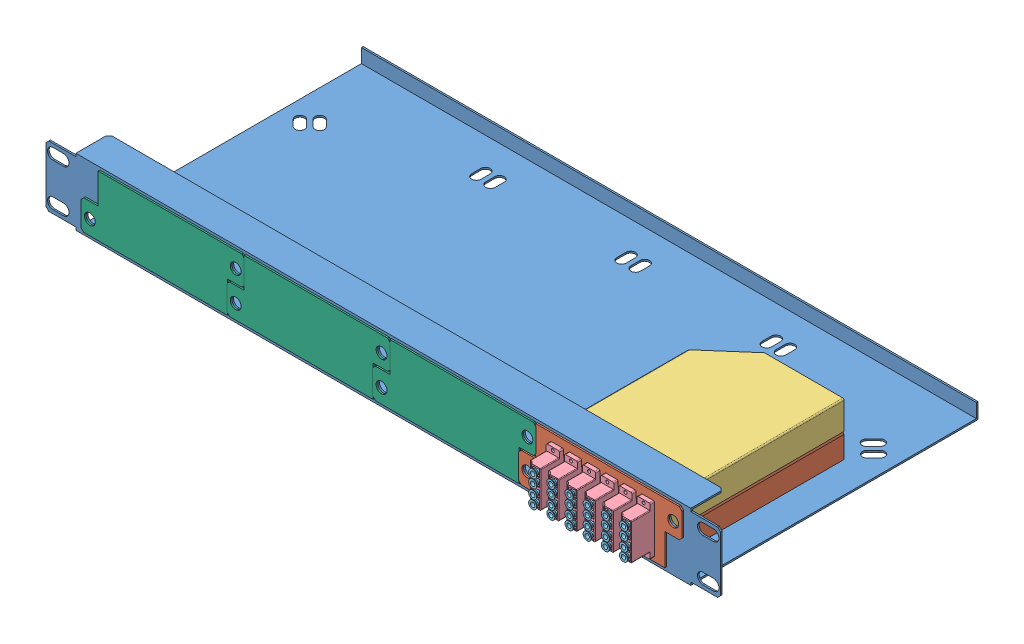
SolidWorks assembly MTP-Pannel, configuration Standard. Lengths in mm.
Overall size (482.6 47.8 225.51).
67 component instances, 6 part files, 15 mates.
Components (placement in the parent):
- 1U Rack Plate-1: 1U Rack Plate [Standard] at (-414.8398 -8.3387 0) size (482.6 47.8 205.5)
- MTP-Casette-1: MTP-Casette [Standard] at (-26.275 -1.825 1.2) size (117 43.2 150.01)
  - Cassette-1: Cassette [Standard] at (-81.5544 -7.2939 -1.2) size (117 43.2 131.2)
  - Cassette Lid-1: Cassette Lid [Standard] at (-38.8731 -6.65 -32.039) size (86.6 20.2 130)
  - LC-Adapter-1: LC-Adapter [Standard] at (-94.18 -5.525 16.25) x (0 1 0) z (0 0 1) size (34.9 10.05 34.47)
    - LC Adaptor-1: LC Adaptor [Standard] at (-28.4856 -9.35 -16.25) x (1 0 0) z (0 -1 0) size (34.9 25.75 9.35)
    - LC Adaptor Dust Cap-1: LC Adaptor Dust Cap [Standard] at (-27.05 -6.075 2.56) x (-0.837169 0.546944 0) z (-0.546944 -0.837169 0) size (5.75 16.66 5.75)
    - LC Adaptor Dust Cap-2: LC Adaptor Dust Cap [Standard] at (-20.85 -6.075 2.56) x (-0.837169 0.546944 0) z (-0.546944 -0.837169 0) size (5.75 16.66 5.75)
    - LC Adaptor Dust Cap-3: LC Adaptor Dust Cap [Standard] at (-14.05 -6.075 2.56) x (-0.837169 0.546944 0) z (-0.546944 -0.837169 0) size (5.75 16.66 5.75)
    - LC Adaptor Dust Cap-4: LC Adaptor Dust Cap [Standard] at (-7.85 -6.075 2.56) x (-0.837169 0.546944 0) z (-0.546944 -0.837169 0) size (5.75 16.66 5.75)
    - LC Adaptor Dust Cap-5: LC Adaptor Dust Cap [Standard] at (-27.05 -6.075 -31.91) x (0.972668 -0.232198 0) z (-0.232198 -0.972668 0) size (5.75 16.66 5.75)
    - LC Adaptor Dust Cap-6: LC Adaptor Dust Cap [Standard] at (-20.85 -6.075 -31.91) x (1 0 0) z (0 -1 0) size (5.75 16.66 5.75)
    - LC Adaptor Dust Cap-7: LC Adaptor Dust Cap [Standard] at (-14.05 -6.075 -31.91) x (0.97427 0.225385 0) z (0.225385 -0.97427 0) size (5.75 16.66 5.75)
    - LC Adaptor Dust Cap-8: LC Adaptor Dust Cap [Standard] at (-7.85 -6.075 -31.91) x (1 0 0) z (0 -1 0) size (5.75 16.66 5.75)
  - LC-Adapter-2: LC-Adapter [Standard] at (-81.18 -5.525 16.25) x (0 1 0) z (0 0 1) size (34.9 10.05 34.47)
    - LC Adaptor-1: LC Adaptor [Standard] at (-28.4856 -9.35 -16.25) x (1 0 0) z (0 -1 0) size (34.9 25.75 9.35)
    - LC Adaptor Dust Cap-1: LC Adaptor Dust Cap [Standard] at (-27.05 -6.075 2.56) x (-0.837169 0.546944 0) z (-0.546944 -0.837169 0) size (5.75 16.66 5.75)
    - LC Adaptor Dust Cap-2: LC Adaptor Dust Cap [Standard] at (-20.85 -6.075 2.56) x (-0.837169 0.546944 0) z (-0.546944 -0.837169 0) size (5.75 16.66 5.75)
    - LC Adaptor Dust Cap-3: LC Adaptor Dust Cap [Standard] at (-14.05 -6.075 2.56) x (-0.837169 0.546944 0) z (-0.546944 -0.837169 0) size (5.75 16.66 5.75)
    - LC Adaptor Dust Cap-4: LC Adaptor Dust Cap [Standard] at (-7.85 -6.075 2.56) x (-0.837169 0.546944 0) z (-0.546944 -0.837169 0) size (5.75 16.66 5.75)
    - LC Adaptor Dust Cap-5: LC Adaptor Dust Cap [Standard] at (-27.05 -6.075 -31.91) x (0.972668 -0.232198 0) z (-0.232198 -0.972668 0) size (5.75 16.66 5.75)
    - LC Adaptor Dust Cap-6: LC Adaptor Dust Cap [Standard] at (-20.85 -6.075 -31.91) x (1 0 0) z (0 -1 0) size (5.75 16.66 5.75)
    - LC Adaptor Dust Cap-7: LC Adaptor Dust Cap [Standard] at (-14.05 -6.075 -31.91) x (0.97427 0.225385 0) z (0.225385 -0.97427 0) size (5.75 16.66 5.75)
    - LC Adaptor Dust Cap-8: LC Adaptor Dust Cap [Standard] at (-7.85 -6.075 -31.91) x (1 0 0) z (0 -1 0) size (5.75 16.66 5.75)
  - LC-Adapter-3: LC-Adapter [Standard] at (-68.18 -5.525 16.25) x (0 1 0) z (0 0 1) size (34.9 10.05 34.47)
    - LC Adaptor-1: LC Adaptor [Standard] at (-28.4856 -9.35 -16.25) x (1 0 0) z (0 -1 0) size (34.9 25.75 9.35)
    - LC Adaptor Dust Cap-1: LC Adaptor Dust Cap [Standard] at (-27.05 -6.075 2.56) x (-0.837169 0.546944 0) z (-0.546944 -0.837169 0) size (5.75 16.66 5.75)
    - LC Adaptor Dust Cap-2: LC Adaptor Dust Cap [Standard] at (-20.85 -6.075 2.56) x (-0.837169 0.546944 0) z (-0.546944 -0.837169 0) size (5.75 16.66 5.75)
    - LC Adaptor Dust Cap-3: LC Adaptor Dust Cap [Standard] at (-14.05 -6.075 2.56) x (-0.837169 0.546944 0) z (-0.546944 -0.837169 0) size (5.75 16.66 5.75)
    - LC Adaptor Dust Cap-4: LC Adaptor Dust Cap [Standard] at (-7.85 -6.075 2.56) x (-0.837169 0.546944 0) z (-0.546944 -0.837169 0) size (5.75 16.66 5.75)
    - LC Adaptor Dust Cap-5: LC Adaptor Dust Cap [Standard] at (-27.05 -6.075 -31.91) x (0.972668 -0.232198 0) z (-0.232198 -0.972668 0) size (5.75 16.66 5.75)
    - LC Adaptor Dust Cap-6: LC Adaptor Dust Cap [Standard] at (-20.85 -6.075 -31.91) x (1 0 0) z (0 -1 0) size (5.75 16.66 5.75)
    - LC Adaptor Dust Cap-7: LC Adaptor Dust Cap [Standard] at (-14.05 -6.075 -31.91) x (0.97427 0.225385 0) z (0.225385 -0.97427 0) size (5.75 16.66 5.75)
    - LC Adaptor Dust Cap-8: LC Adaptor Dust Cap [Standard] at (-7.85 -6.075 -31.91) x (1 0 0) z (0 -1 0) size (5.75 16.66 5.75)
  - LC-Adapter-4: LC-Adapter [Standard] at (-55.18 -5.525 16.25) x (0 1 0) z (0 0 1) size (34.9 10.05 34.47)
    - LC Adaptor-1: LC Adaptor [Standard] at (-28.4856 -9.35 -16.25) x (1 0 0) z (0 -1 0) size (34.9 25.75 9.35)
    - LC Adaptor Dust Cap-1: LC Adaptor Dust Cap [Standard] at (-27.05 -6.075 2.56) x (-0.837169 0.546944 0) z (-0.546944 -0.837169 0) size (5.75 16.66 5.75)
    - LC Adaptor Dust Cap-2: LC Adaptor Dust Cap [Standard] at (-20.85 -6.075 2.56) x (-0.837169 0.546944 0) z (-0.546944 -0.837169 0) size (5.75 16.66 5.75)
    - LC Adaptor Dust Cap-3: LC Adaptor Dust Cap [Standard] at (-14.05 -6.075 2.56) x (-0.837169 0.546944 0) z (-0.546944 -0.837169 0) size (5.75 16.66 5.75)
    - LC Adaptor Dust Cap-4: LC Adaptor Dust Cap [Standard] at (-7.85 -6.075 2.56) x (-0.837169 0.546944 0) z (-0.546944 -0.837169 0) size (5.75 16.66 5.75)
    - LC Adaptor Dust Cap-5: LC Adaptor Dust Cap [Standard] at (-27.05 -6.075 -31.91) x (0.972668 -0.232198 0) z (-0.232198 -0.972668 0) size (5.75 16.66 5.75)
    - LC Adaptor Dust Cap-6: LC Adaptor Dust Cap [Standard] at (-20.85 -6.075 -31.91) x (1 0 0) z (0 -1 0) size (5.75 16.66 5.75)
    - LC Adaptor Dust Cap-7: LC Adaptor Dust Cap [Standard] at (-14.05 -6.075 -31.91) x (0.97427 0.225385 0) z (0.225385 -0.97427 0) size (5.75 16.66 5.75)
    - LC Adaptor Dust Cap-8: LC Adaptor Dust Cap [Standard] at (-7.85 -6.075 -31.91) x (1 0 0) z (0 -1 0) size (5.75 16.66 5.75)
  - LC-Adapter-5: LC-Adapter [Standard] at (-42.18 -5.525 16.25) x (0 1 0) z (0 0 1) size (34.9 10.05 34.47)
    - LC Adaptor-1: LC Adaptor [Standard] at (-28.4856 -9.35 -16.25) x (1 0 0) z (0 -1 0) size (34.9 25.75 9.35)
    - LC Adaptor Dust Cap-1: LC Adaptor Dust Cap [Standard] at (-27.05 -6.075 2.56) x (-0.837169 0.546944 0) z (-0.546944 -0.837169 0) size (5.75 16.66 5.75)
    - LC Adaptor Dust Cap-2: LC Adaptor Dust Cap [Standard] at (-20.85 -6.075 2.56) x (-0.837169 0.546944 0) z (-0.546944 -0.837169 0) size (5.75 16.66 5.75)
    - LC Adaptor Dust Cap-3: LC Adaptor Dust Cap [Standard] at (-14.05 -6.075 2.56) x (-0.837169 0.546944 0) z (-0.546944 -0.837169 0) size (5.75 16.66 5.75)
    - LC Adaptor Dust Cap-4: LC Adaptor Dust Cap [Standard] at (-7.85 -6.075 2.56) x (-0.837169 0.546944 0) z (-0.546944 -0.837169 0) size (5.75 16.66 5.75)
    - LC Adaptor Dust Cap-5: LC Adaptor Dust Cap [Standard] at (-27.05 -6.075 -31.91) x (0.972668 -0.232198 0) z (-0.232198 -0.972668 0) size (5.75 16.66 5.75)
    - LC Adaptor Dust Cap-6: LC Adaptor Dust Cap [Standard] at (-20.85 -6.075 -31.91) x (1 0 0) z (0 -1 0) size (5.75 16.66 5.75)
    - LC Adaptor Dust Cap-7: LC Adaptor Dust Cap [Standard] at (-14.05 -6.075 -31.91) x (0.97427 0.225385 0) z (0.225385 -0.97427 0) size (5.75 16.66 5.75)
    - LC Adaptor Dust Cap-8: LC Adaptor Dust Cap [Standard] at (-7.85 -6.075 -31.91) x (1 0 0) z (0 -1 0) size (5.75 16.66 5.75)
  - LC-Adapter-6: LC-Adapter [Standard] at (-29.18 -5.525 16.25) x (0 1 0) z (0 0 1) size (34.9 10.05 34.47)
    - LC Adaptor-1: LC Adaptor [Standard] at (-28.4856 -9.35 -16.25) x (1 0 0) z (0 -1 0) size (34.9 25.75 9.35)
    - LC Adaptor Dust Cap-1: LC Adaptor Dust Cap [Standard] at (-27.05 -6.075 2.56) x (-0.837169 0.546944 0) z (-0.546944 -0.837169 0) size (5.75 16.66 5.75)
    - LC Adaptor Dust Cap-2: LC Adaptor Dust Cap [Standard] at (-20.85 -6.075 2.56) x (-0.837169 0.546944 0) z (-0.546944 -0.837169 0) size (5.75 16.66 5.75)
    - LC Adaptor Dust Cap-3: LC Adaptor Dust Cap [Standard] at (-14.05 -6.075 2.56) x (-0.837169 0.546944 0) z (-0.546944 -0.837169 0) size (5.75 16.66 5.75)
    - LC Adaptor Dust Cap-4: LC Adaptor Dust Cap [Standard] at (-7.85 -6.075 2.56) x (-0.837169 0.546944 0) z (-0.546944 -0.837169 0) size (5.75 16.66 5.75)
    - LC Adaptor Dust Cap-5: LC Adaptor Dust Cap [Standard] at (-27.05 -6.075 -31.91) x (0.972668 -0.232198 0) z (-0.232198 -0.972668 0) size (5.75 16.66 5.75)
    - LC Adaptor Dust Cap-6: LC Adaptor Dust Cap [Standard] at (-20.85 -6.075 -31.91) x (1 0 0) z (0 -1 0) size (5.75 16.66 5.75)
    - LC Adaptor Dust Cap-7: LC Adaptor Dust Cap [Standard] at (-14.05 -6.075 -31.91) x (0.97427 0.225385 0) z (0.225385 -0.97427 0) size (5.75 16.66 5.75)
    - LC Adaptor Dust Cap-8: LC Adaptor Dust Cap [Standard] at (-7.85 -6.075 -31.91) x (1 0 0) z (0 -1 0) size (5.75 16.66 5.75)
- Cassette-Blind-1: Cassette-Blind [Standard] at (-212.1794 -9.1189 0) size (117 43.2 1.2)
- Cassette-Blind-2: Cassette-Blind [Standard] at (-316.5294 -9.1189 0) size (117 43.2 1.2)
- Cassette-Blind-3: Cassette-Blind [Standard] at (-420.8794 -9.1189 0) size (117 43.2 1.2)
Mates (geometry in assembly coordinates):
- Deckungsgleich1: coincident aligned: plane of 1U Rack Plate-1 through (-414.8398 -8.3387 0) normal (0 0 1); plane of assembly
- Deckungsgleich2: coincident aligned: plane of 1U Rack Plate-1 through (-21.2 0 -1.2) normal (0 1 0); plane of assembly
- Deckungsgleich3: coincident aligned: plane of 1U Rack Plate-1 through (0 -8.3387 0) normal (1 0 0); plane of assembly
- Deckungsgleich4: coincident: plane of 1U Rack Plate-1 through (-414.8398 -8.3387 0) normal (0 0 1); plane of MTP-Casette-1/Cassette-1 through (-107.8294 -9.1189 0) normal (0 0 -1)
- Konzentrisch1: concentric: cylinder of 1U Rack Plate-1 through (-32.6 -13.175 -1.4) axis (0 0 1) radius 3.9; cylinder of MTP-Casette-1/Cassette-1 through (-32.6 -13.175 -0.2) axis (0 0 1) radius 3.9
- Konzentrisch2: concentric aligned: cylinder of 1U Rack Plate-1 through (-136.95 -34.625 -1.4) axis (0 0 1) radius 3.9; cylinder of MTP-Casette-1/Cassette-1 through (-136.95 -34.625 -0.2) axis (0 0 1) radius 3.9
- Deckungsgleich5: coincident: plane of 1U Rack Plate-1 through (-414.8398 -8.3387 0) normal (0 0 1); plane of Cassette-Blind-3 through (-420.8794 -9.1189 0) normal (0 0 -1)
- Deckungsgleich6: coincident: plane of 1U Rack Plate-1 through (-414.8398 -8.3387 0) normal (0 0 1); plane of Cassette-Blind-2 through (-316.5294 -9.1189 0) normal (0 0 -1)
- Deckungsgleich7: coincident: plane of 1U Rack Plate-1 through (-414.8398 -8.3387 0) normal (0 0 1); plane of Cassette-Blind-1 through (-212.1794 -9.1189 0) normal (0 0 -1)
- Konzentrisch3: concentric: cylinder of 1U Rack Plate-1 through (-136.95 -13.175 -1.4) axis (0 0 1) radius 3.9671; cylinder of Cassette-Blind-1 through (-136.95 -13.175 1.2) axis (0 0 -1) radius 3.9
- Konzentrisch4: concentric anti-aligned: cylinder of 1U Rack Plate-1 through (-241.3 -34.625 -1.4) axis (0 0 1) radius 3.9; cylinder of Cassette-Blind-1 through (-241.3 -34.625 1.2) axis (0 0 -1) radius 3.9
- Konzentrisch5: concentric: cylinder of 1U Rack Plate-1 through (-241.3 -13.175 -1.4) axis (0 0 1) radius 3.9455; cylinder of Cassette-Blind-2 through (-241.3 -13.175 1.2) axis (0 0 -1) radius 3.9
- Konzentrisch6: concentric anti-aligned: cylinder of 1U Rack Plate-1 through (-345.65 -34.625 -1.4) axis (0 0 1) radius 4.0856; cylinder of Cassette-Blind-2 through (-345.65 -34.625 1.2) axis (0 0 -1) radius 3.9
- Konzentrisch7: concentric: cylinder of 1U Rack Plate-1 through (-345.65 -13.175 -1.4) axis (0 0 1) radius 3.8809; cylinder of Cassette-Blind-3 through (-345.65 -13.175 1.2) axis (0 0 -1) radius 3.9
- Konzentrisch8: concentric anti-aligned: cylinder of 1U Rack Plate-1 through (-450 -34.625 -1.4) axis (0 0 1) radius 3.9; cylinder of Cassette-Blind-3 through (-450 -34.625 1.2) axis (0 0 -1) radius 3.9
